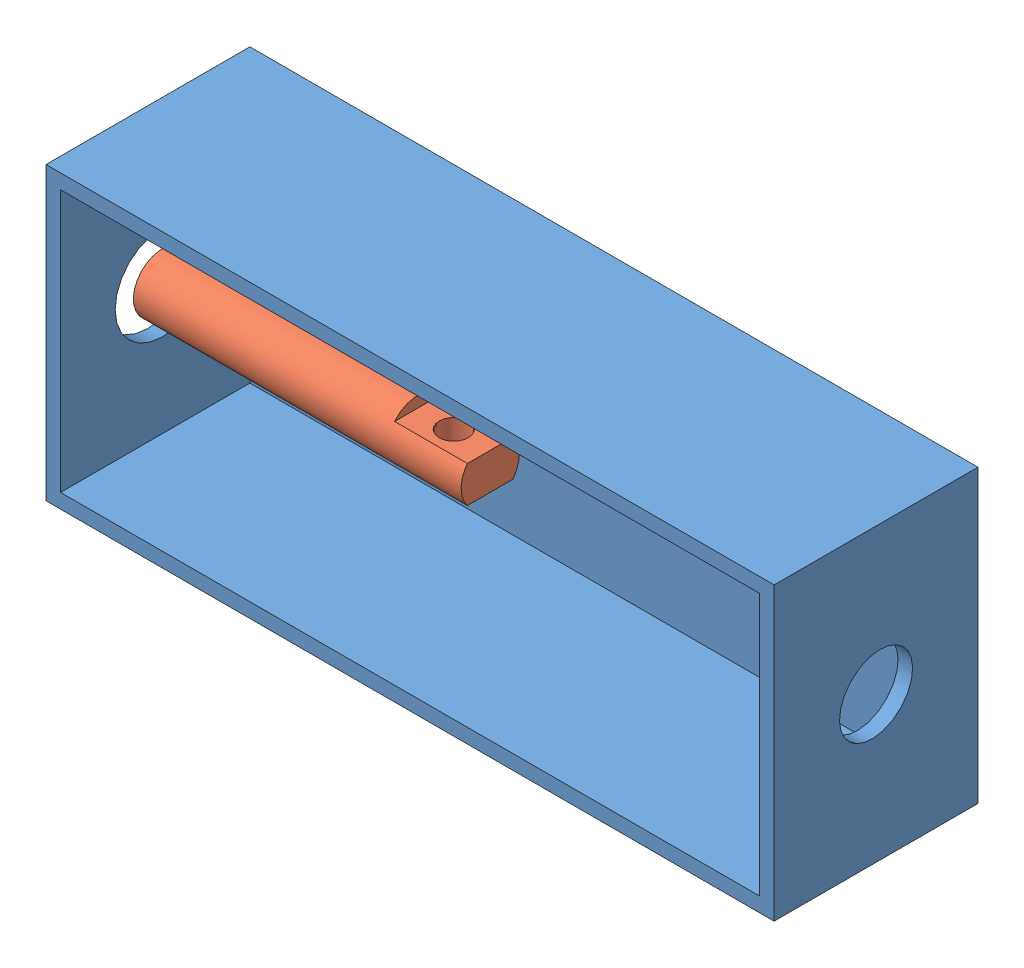
SolidWorks assembly 测绘装配，只允许千进60毫米, configuration 默认. Lengths in mm.
Overall size (200 80 56).
2 component instances, 2 part files, 3 mates.
Components (placement in the parent):
- 箱体-1: 箱体 [默认] at origin size (200 80 56)
- 伸出最长的长度-1: 伸出最长的长度 [默认] at (-6 0 28) x (-1 0 0) z (0 -1 0) size (90 16 16)
Mates (geometry in assembly coordinates):
- 同心1: concentric anti-aligned: circle of 箱体-1; circle of 伸出最长的长度-1
- 重合1: coincident anti-aligned: plane of 箱体-1 through (-96 36 4) normal (1 0 0); plane of 伸出最长的长度-1 through (-96 0 28) normal (-1 0 0)
- 平行1: parallel anti-aligned: plane of 箱体-1 through (-96 36 4) normal (0 -1 0); plane of 伸出最长的长度-1 through (-26 5 18) normal (0 1 0)
